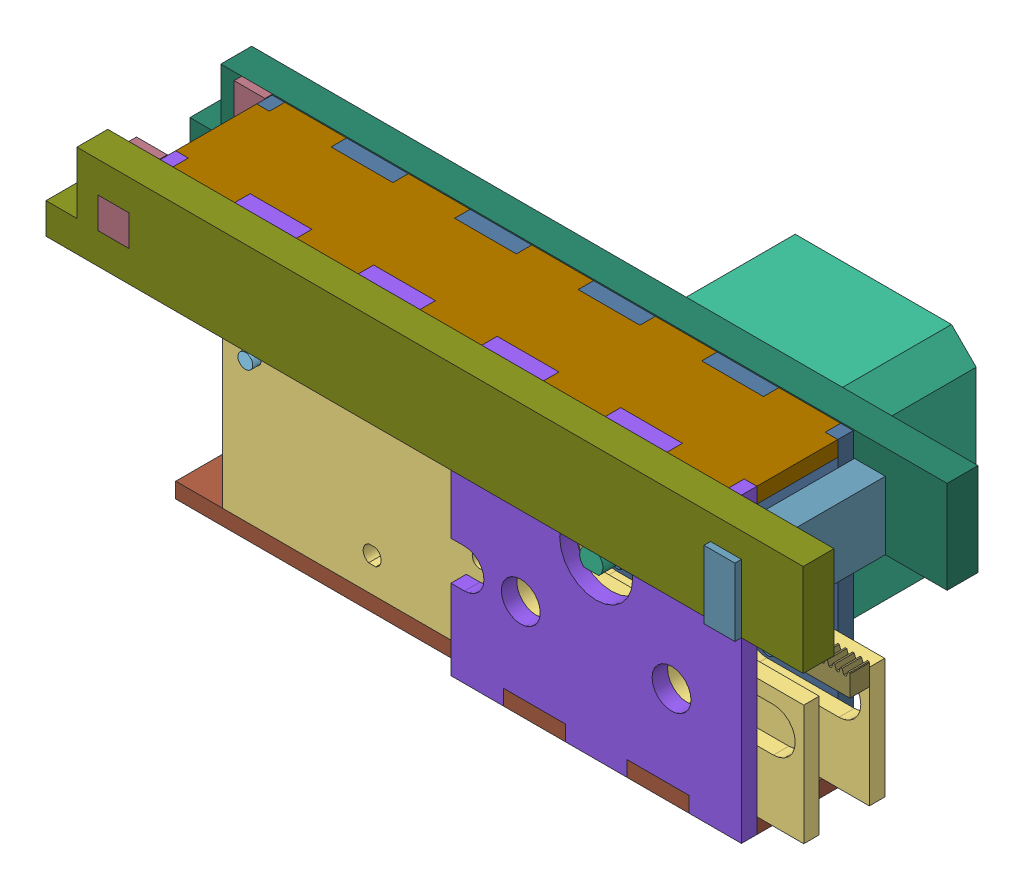
SolidWorks assembly leverSupport, configuration Default. Lengths in mm.
Overall size (155.7 62.02 64.69).
20 component instances, 16 part files, 14 mates.
Components (placement in the parent):
- D2RV_L13-1: D2RV_L13 [Default] at (-66.0431 0.3914 47.3736) size (146.27 62.02 58)
  - D2RV_L13_BASE-1: D2RV_L13_BASE [Default] at origin size (37.8 17.39 10.3)
  - D2RV_L13_ACTUATOR-1: D2RV_L13_ACTUATOR [Default] at (-8.6 2.8 -0.2) x (0.986964 0.160939 0) z (0 0 1) size (28.5 9 4.3)
  - leverMount-1: leverMount [Default] at (-23.075 10.5375 5.15) x (0 0 1) z (-1 0 0) size (3.17 55.68 119.5)
  - secondLever-1: secondLever [Default] at (-22.9775 7.8023 4.5625) x (0 0 -1) z (-0.98879 0.149315 0) size (9.53 6.35 57.15)
  - Pin-1: Pin [Default] at (-46.6 12.975 -9.0425) x (0.883639 -0.468168 0) z (0 0 1) size (3.07 3.07 19.05)
  - leverMount-2: leverMount [Default] at (-23.075 10.5375 -8.325) x (0 0 1) z (-1 0 0) size (3.17 55.68 119.5)
  - motor-1: motor [Default] at (27.0334 15.4 -11.5) x (1 0 0) z (0 1 0) size (42.3 58 42.3)
  - pinion-1: pinion [Default] at (27.0334 15.4 -4.4788) x (0.997942 0.064122 0) z (0.064122 -0.997942 0) size (15.59 8 15.62)
  - leverMotorMount2-1: leverMotorMount2 [Default] at (-7.5506 15.7619 15.6501) x (0 0 1) z (1 0 0) size (23 62.02 119.5)
    - leverMotorMount_Right-1: leverMotorMount_Right [Default] at (-15.6501 -25.7881 -55.041) size (3.17 62.02 119.5)
    - leverMotorMount_Bottom-1: leverMotorMount_Bottom [Default] at (-15.6501 -25.7881 -55.041) size (23 3.17 119.5)
    - leverMotorMount_Left-1: leverMotorMount_Left [Default] at (-15.6501 -25.7881 -55.041) size (3.17 62.02 119.5)
    - leverMotorMount_Top-1: leverMotorMount_Top [Default] at (-15.6501 -25.7881 -55.041) size (23 3.17 119.5)
  - railSmall-1: railSmall [Default] at (6.8 3.9 -1.15) size (59.75 4.5 4)
- leverSupportStop-1: leverSupportStop [Default] at (-135.1187 32.4164 35.6326) x (1 0 0) z (0 1 0) size (6.35 7.94 19.05)
- leverSupportStop-2: leverSupportStop [Default] at (-135.1187 32.4164 58.8736) x (1 0 0) z (0 -1 0) size (6.35 7.94 19.05)
- leverSupportEndstop-1: leverSupportEndstop [Default] at (-9.1347 29.8764 47.5169) size (6.35 13.97 38.1)
- leverSupportLeft-1: leverSupportLeft [Default] at (-68.9517 41.9414 47.2531) x (0 0 1) z (1 0 0) size (6.35 19.05 155.7)
- leverSupportRight-1: leverSupportRight [Default] at (-68.9517 41.9414 47.2531) x (0 0 1) z (1 0 0) size (6.35 19.05 155.7)
Mates (geometry in assembly coordinates):
- Coincident7: coincident: plane of leverSupportEndstop-1 through (-2.7847 36.8614 66.5669) normal (0 1 0); plane of leverSupportLeft-1 through (-9.1347 36.8614 65.2236) normal (0 -1 0)
- Coincident8: coincident: plane of leverSupportEndstop-1 through (-2.7847 29.8764 47.5169) normal (1 0 0); plane of leverSupportLeft-1 through (-2.7847 22.8914 65.2236) normal (-1 0 0)
- Coincident9: coincident: plane of leverSupportEndstop-1 through (-2.7847 36.8614 66.5669) normal (0 1 0); plane of leverSupportRight-1 through (-9.1347 36.8614 65.2236) normal (0 -1 0)
- Coincident10: coincident: plane of leverSupportEndstop-1 through (-9.1347 29.8764 47.5169) normal (-1 0 0); plane of leverSupportRight-1 through (-9.1347 22.8914 65.2236) normal (1 0 0)
- Coincident11: coincident: plane of leverSupportStop-1 through (-135.1187 32.4164 35.6326) normal (-1 0 0); plane of leverSupportLeft-1 through (-135.1187 29.2414 65.2236) normal (1 0 0)
- Coincident12: coincident: plane of leverSupportStop-1 through (-128.7687 29.2414 35.6326) normal (0 -1 0); plane of leverSupportLeft-1 through (-135.1187 29.2414 65.2236) normal (0 1 0)
- Coincident13: coincident: plane of leverSupportStop-1 through (-128.7687 29.2414 29.2826) normal (0 0 -1); plane of leverSupportLeft-1 through (9.9153 22.8914 29.2826) normal (0 0 -1)
- Coincident14: coincident: plane of leverSupportStop-2 through (-135.1187 32.4164 58.8736) normal (-1 0 0); plane of leverSupportRight-1 through (-135.1187 29.2414 65.2236) normal (1 0 0)
- Coincident15: coincident: plane of leverSupportStop-2 through (-128.7687 29.2414 58.8736) normal (0 -1 0); plane of leverSupportRight-1 through (-135.1187 29.2414 65.2236) normal (0 1 0)
- Coincident16: coincident: plane of leverSupportStop-2 through (-128.7687 35.5914 65.2236) normal (0 0 1); plane of leverSupportRight-1 through (-145.7867 22.8914 65.2236) normal (0 0 1)
- Distance1: distance = 23.241 mm: plane of leverSupportRight-1 through (-128.7687 22.8914 58.8736) normal (0 0 -1); plane of leverSupportLeft-1 through (-9.1347 22.8914 35.6326) normal (0 0 1)
- Coincident18: coincident: plane of D2RV_L13-1/leverMotorMount2-1/leverMotorMount_Right-1 through (-9.1347 41.9414 47.3736) normal (1 0 0); plane of leverSupportEndstop-1 through (-9.1347 29.8764 47.5169) normal (-1 0 0)
- Coincident19: coincident: plane of D2RV_L13-1/leverMotorMount2-1/leverMotorMount_Right-1 through (-9.1347 -20.0836 58.8736) normal (0 0 1); plane of leverSupportRight-1 through (-128.7687 22.8914 58.8736) normal (0 0 -1)
- Coincident20: coincident: plane of D2RV_L13-1/leverMotorMount2-1/leverMotorMount_Bottom-1 through (-9.1347 41.9414 58.8736) normal (0 1 0); plane of leverSupportLeft-1 through (-68.9517 41.9414 47.2531) normal (0 1 0)
